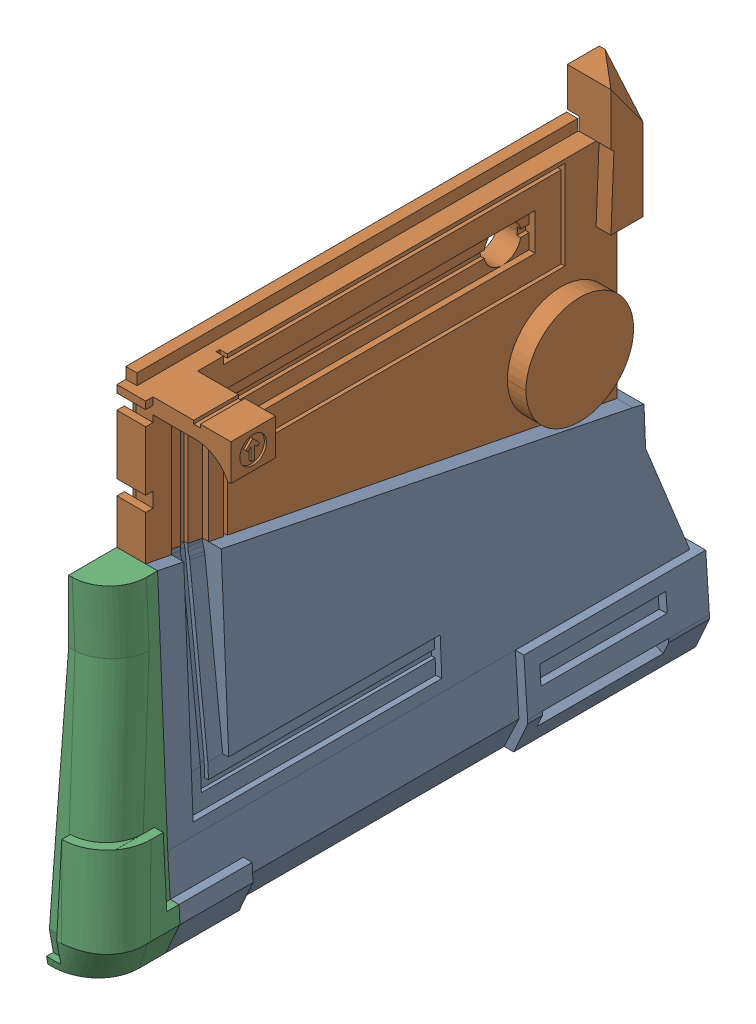
SolidWorks assembly body-left, configuration Default. Lengths in mm.
Overall size (47.92 238.33 272.05).
2 component instances, 2 part files, 1 mates.
Components (placement in the parent):
- body-left-back-1: body-left-back [Default] at (-53.1878 -51.8815 63.3141) size (47.92 238.33 237.83)
- body-left-front-1: body-left-front [Default] at (-53.1878 -51.8815 63.3141) size (28.33 146.67 34.22)
Mates (geometry in assembly coordinates):
- Coincident1: coincident anti-aligned: circle of body-left-back-1; circle of body-left-front-1
